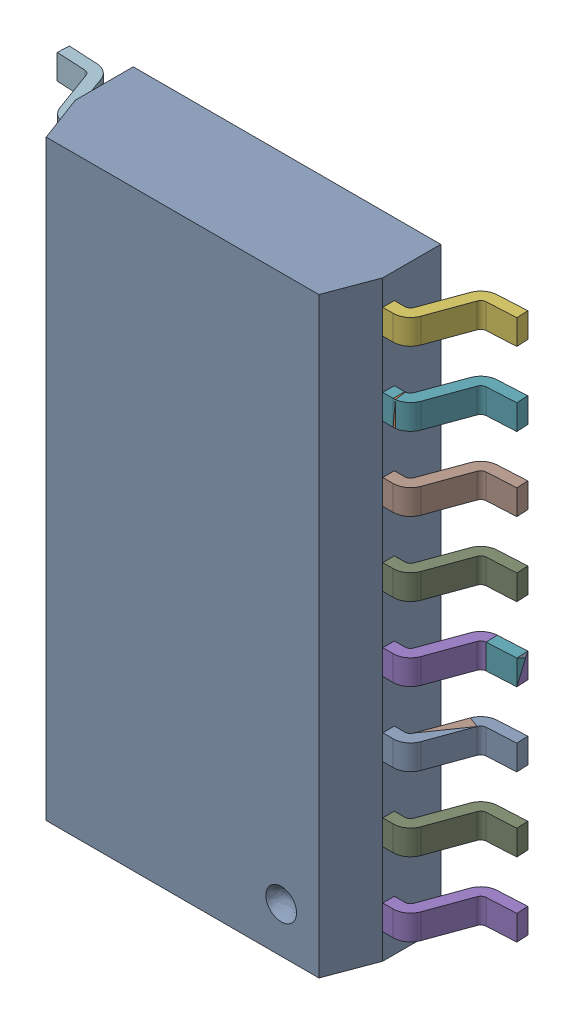
SolidWorks assembly User Library-SOP16_208mil (5.3mm), configuration ﾃﾞﾌｫﾙﾄ. Lengths in mm.
Overall size (7.92 10.2 2.07).
29 component instances, 2 part files, 0 mates.
Components (placement in the parent):
- SOP16 Body-1: SOP16 Body [ﾃﾞﾌｫﾙﾄ] at origin size (5.3 10.2 1.87)
- Foot SOP16-1: Foot SOP16 [ﾃﾞﾌｫﾙﾄ] at (3.95 -0.85 -0.1979) x (-1 0 0) z (0 0 1) size (1.31 0.43 1.2)
- Foot SOP16-2: Foot SOP16 [ﾃﾞﾌｫﾙﾄ] at (3.95 -2.12 -0.1979) x (-1 0 0) z (0 0 1) size (1.31 0.43 1.2)
- Foot SOP16-3: Foot SOP16 [ﾃﾞﾌｫﾙﾄ] at (3.95 -3.39 -0.1979) x (-1 0 0) z (0 0 1) size (1.31 0.43 1.2)
- Foot SOP16-4: Foot SOP16 [ﾃﾞﾌｫﾙﾄ] at (3.95 -4.66 -0.1979) x (-1 0 0) z (0 0 1) size (1.31 0.43 1.2)
- Foot SOP16-5: Foot SOP16 [ﾃﾞﾌｫﾙﾄ] at (3.95 0.42 -0.1979) x (-1 0 0) z (0 0 1) size (1.31 0.43 1.2)
- Foot SOP16-6: Foot SOP16 [ﾃﾞﾌｫﾙﾄ] at (3.95 -0.85 -0.1979) x (-1 0 0) z (0 0 1) size (1.31 0.43 1.2)
- Foot SOP16-7: Foot SOP16 [ﾃﾞﾌｫﾙﾄ] at (3.95 -2.12 -0.1979) x (-1 0 0) z (0 0 1) size (1.31 0.43 1.2)
- Foot SOP16-8: Foot SOP16 [ﾃﾞﾌｫﾙﾄ] at (3.95 -3.39 -0.1979) x (-1 0 0) z (0 0 1) size (1.31 0.43 1.2)
- Foot SOP16-9: Foot SOP16 [ﾃﾞﾌｫﾙﾄ] at (3.95 1.69 -0.1979) x (-1 0 0) z (0 0 1) size (1.31 0.43 1.2)
- Foot SOP16-10: Foot SOP16 [ﾃﾞﾌｫﾙﾄ] at (3.95 0.42 -0.1979) x (-1 0 0) z (0 0 1) size (1.31 0.43 1.2)
- Foot SOP16-11: Foot SOP16 [ﾃﾞﾌｫﾙﾄ] at (3.95 -0.85 -0.1979) x (-1 0 0) z (0 0 1) size (1.31 0.43 1.2)
- Foot SOP16-12: Foot SOP16 [ﾃﾞﾌｫﾙﾄ] at (3.95 -2.12 -0.1979) x (-1 0 0) z (0 0 1) size (1.31 0.43 1.2)
- Foot SOP16-13: Foot SOP16 [ﾃﾞﾌｫﾙﾄ] at (3.95 2.96 -0.1979) x (-1 0 0) z (0 0 1) size (1.31 0.43 1.2)
- Foot SOP16-14: Foot SOP16 [ﾃﾞﾌｫﾙﾄ] at (3.95 1.69 -0.1979) x (-1 0 0) z (0 0 1) size (1.31 0.43 1.2)
- Foot SOP16-15: Foot SOP16 [ﾃﾞﾌｫﾙﾄ] at (3.95 0.42 -0.1979) x (-1 0 0) z (0 0 1) size (1.31 0.43 1.2)
- Foot SOP16-16: Foot SOP16 [ﾃﾞﾌｫﾙﾄ] at (3.95 -0.85 -0.1979) x (-1 0 0) z (0 0 1) size (1.31 0.43 1.2)
- Foot SOP16-17: Foot SOP16 [ﾃﾞﾌｫﾙﾄ] at (3.95 4.23 -0.1979) x (-1 0 0) z (0 0 1) size (1.31 0.43 1.2)
- Foot SOP16-18: Foot SOP16 [ﾃﾞﾌｫﾙﾄ] at (3.95 2.96 -0.1979) x (-1 0 0) z (0 0 1) size (1.31 0.43 1.2)
- Foot SOP16-19: Foot SOP16 [ﾃﾞﾌｫﾙﾄ] at (3.95 1.69 -0.1979) x (-1 0 0) z (0 0 1) size (1.31 0.43 1.2)
- Foot SOP16-20: Foot SOP16 [ﾃﾞﾌｫﾙﾄ] at (3.95 0.42 -0.1979) x (-1 0 0) z (0 0 1) size (1.31 0.43 1.2)
- Foot SOP16-21: Foot SOP16 [ﾃﾞﾌｫﾙﾄ] at (-3.95 2.12 -0.1979) size (1.31 0.43 1.2)
- Foot SOP16-22: Foot SOP16 [ﾃﾞﾌｫﾙﾄ] at (-3.95 3.39 -0.1979) size (1.31 0.43 1.2)
- Foot SOP16-23: Foot SOP16 [ﾃﾞﾌｫﾙﾄ] at (-3.95 4.66 -0.1979) size (1.31 0.43 1.2)
- Foot SOP16-24: Foot SOP16 [ﾃﾞﾌｫﾙﾄ] at (-3.95 0.85 -0.1979) size (1.31 0.43 1.2)
- Foot SOP16-25: Foot SOP16 [ﾃﾞﾌｫﾙﾄ] at (-3.95 -2.96 -0.1979) size (1.31 0.43 1.2)
- Foot SOP16-26: Foot SOP16 [ﾃﾞﾌｫﾙﾄ] at (-3.95 -4.23 -0.1979) size (1.31 0.43 1.2)
- Foot SOP16-27: Foot SOP16 [ﾃﾞﾌｫﾙﾄ] at (-3.95 -1.69 -0.1979) size (1.31 0.43 1.2)
- Foot SOP16-28: Foot SOP16 [ﾃﾞﾌｫﾙﾄ] at (-3.95 -0.42 -0.1979) size (1.31 0.43 1.2)
